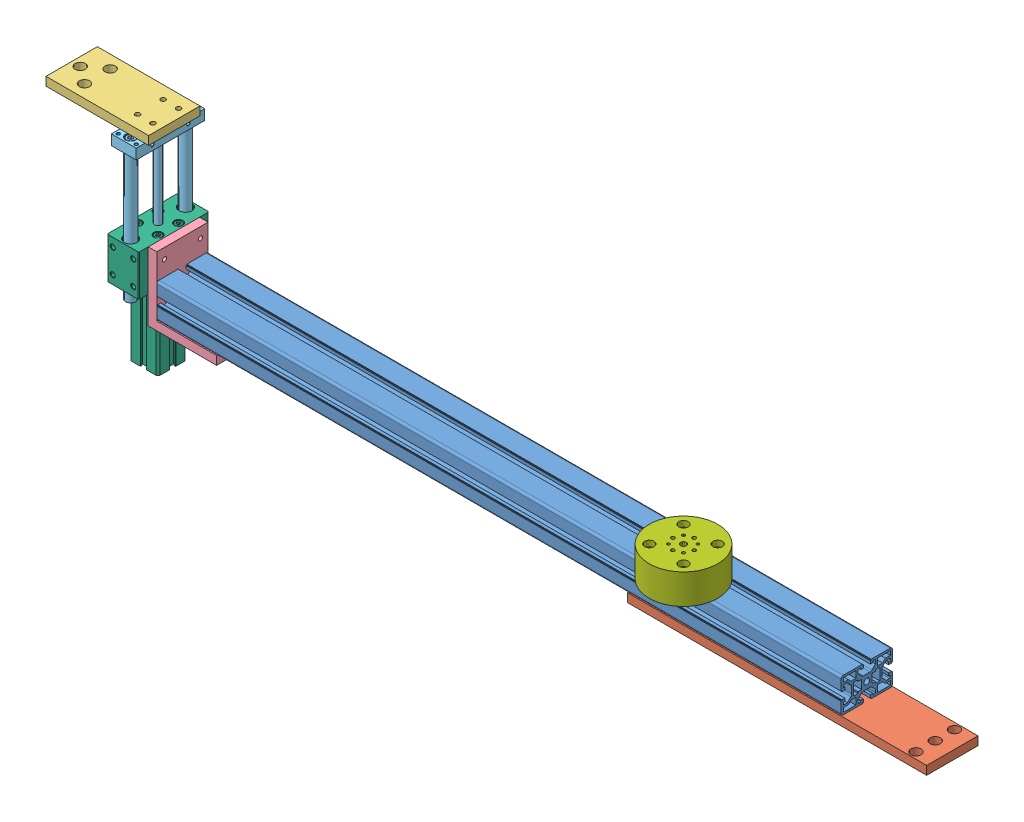
SolidWorks assembly 抓件部分, configuration 默认. Lengths in mm.
Overall size (1029.5 251.42 103.95).
7 component instances, 7 part files, 17 mates.
Components (placement in the parent):
- 高型一字连接铝型材-1: 高型一字连接铝型材 [默认<按加工>] at (-22.1877 1342.25 12.93) x (1 0 0) z (0 -1 0) size (800 60 40)
- 吸盘连接块-1: 吸盘连接块 [默认] at (702.8123 1322.25 12.93) x (1 0 0) z (0 -1 0) size (350 60 10)
- 吸盘连接块1-1: 吸盘连接块1 [默认] at (-91.6877 1495.1678 12.93) x (0 0 -1) z (0 1 0) size (60 130.69 10)
- 气缸连接块-2: 气缸连接块 [默认] at (-32.1877 1312.25 -17.07) size (80 80 60)
- _JCB-20x100_R-1: _JCB-20x100_R [默认] at (-50.6877 1479.1678 12.93) x (0 0 -1) z (0 1 0) size (80 29 164)
- _JCB-20x100_B-1: _JCB-20x100_B [默认] at (-50.6877 1392.25 12.93) x (0 0 -1) z (0 1 0) size (82 37 138.5)
- 吸盘连接盘-1: 吸盘连接盘 [默认] at (586.5001 1362.25 35.8843) size (80 35 80)
Mates (geometry in assembly coordinates):
- 距离1: distance = 100 mm aligned: plane of 吸盘连接块-1 through (877.8123 1312.25 42.93) normal (1 0 0); plane of 高型一字连接铝型材-1 through (777.8123 1325.75 22.18) normal (1 0 0)
- 重合4: coincident anti-aligned: plane of 高型一字连接铝型材-1 through (777.8123 1322.25 7.83) normal (0 -1 0); plane of 吸盘连接块-1 through (702.8123 1322.25 12.93) normal (0 1 0)
- 重合5: coincident aligned: plane of 高型一字连接铝型材-1 through (777.8123 1324.75 -17.07) normal (0 0 -1); plane of 吸盘连接块-1 through (527.8123 1312.25 -17.07) normal (0 0 -1)
- 重合7: coincident anti-aligned: plane of 高型一字连接铝型材-1 through (777.8123 1322.25 7.83) normal (0 -1 0); plane of 气缸连接块-2 through (-22.1877 1322.25 42.93) normal (0 1 0)
- 重合8: coincident aligned: plane of 高型一字连接铝型材-1 through (777.8123 1324.75 -17.07) normal (0 0 -1); plane of 气缸连接块-2 through (-32.1877 1312.25 -17.07) normal (0 0 -1)
- 同心3: concentric aligned: cylinder of _JCB-20x100_R-1 through (-50.6877 1495.1678 -19.07) axis (0 -1 0) radius 6; cylinder of _JCB-20x100_B-1 through (-50.6877 1392.25 -19.07) axis (0 -1 0) radius 7
- 同心4: concentric aligned: cylinder of _JCB-20x100_R-1 through (-50.6877 1346.1678 12.93) axis (0 1 0) radius 4; cylinder of _JCB-20x100_B-1 through (-50.6877 1259.25 12.93) axis (0 1 0) radius 10
- LimitDistance2: limit distance = 13.0822 mm anti-aligned: plane of _JCB-20x100_R-1 through (-54.6877 1354.6678 12.93) normal (0 1 0); plane of _JCB-20x100_B-1 through (-54.6877 1367.75 12.93) normal (0 -1 0)
- 距离3: distance = 0 mm anti-aligned: plane of 气缸连接块-2 through (-22.1877 1392.25 42.93) normal (1 0 0); plane of 高型一字连接铝型材-1 through (-22.1877 1325.75 22.18) normal (-1 0 0)
- 宽度1: width aligned: plane of 气缸连接块-2 through (-32.1877 1312.25 -17.07) normal (0 0 -1); plane of _JCB-20x100_R-1 through (-32.1877 1312.25 42.93) normal (0 0 1); plane of 气缸连接块-2 through (-36.1877 1483.1678 -27.07) normal (0 0 -1); plane of _JCB-20x100_R-1 through (-65.1877 1483.1678 52.93) normal (0 0 1)
- 重合15: coincident anti-aligned: plane of 气缸连接块-2 through (-32.1877 1392.25 42.93) normal (-1 0 0); plane of _JCB-20x100_B-1 through (-32.1877 1344.25 52.93) normal (1 0 0)
- 重合16: coincident aligned: plane of 气缸连接块-2 through (-32.1877 1392.25 42.93) normal (0 1 0); plane of _JCB-20x100_B-1 through (-50.6877 1392.25 12.93) normal (0 1 0)
- 重合17: coincident anti-aligned: plane of 吸盘连接块1-1 through (-91.6877 1495.1678 12.93) normal (0 -1 0); plane of _JCB-20x100_R-1 through (-50.6877 1495.1678 12.93) normal (0 1 0)
- 平行2: parallel aligned: plane of 吸盘连接块1-1 through (-151.6877 1505.1678 42.93) normal (0 0 1); plane of _JCB-20x100_R-1 through (-65.1877 1483.1678 52.93) normal (0 0 1)
- 同心9: concentric anti-aligned: cylinder of 吸盘连接块1-1 through (-41.6877 1505.1678 -2.07) axis (0 1 0) radius 2.75; cylinder of _JCB-20x100_R-1 through (-41.6877 1495.1678 -2.07) axis (0 -1 0) radius 2.067
- 同心10: concentric anti-aligned: cylinder of 吸盘连接块1-1 through (-41.6877 1505.1678 27.93) axis (0 1 0) radius 2.75; cylinder of _JCB-20x100_R-1 through (-41.6877 1495.1678 27.93) axis (0 -1 0) radius 2.067
- 重合21: coincident anti-aligned: plane of 高型一字连接铝型材-1 through (777.8123 1362.25 -14.57) normal (0 1 0); plane of 吸盘连接盘-1 through (586.5001 1362.25 35.8843) normal (0 -1 0)
